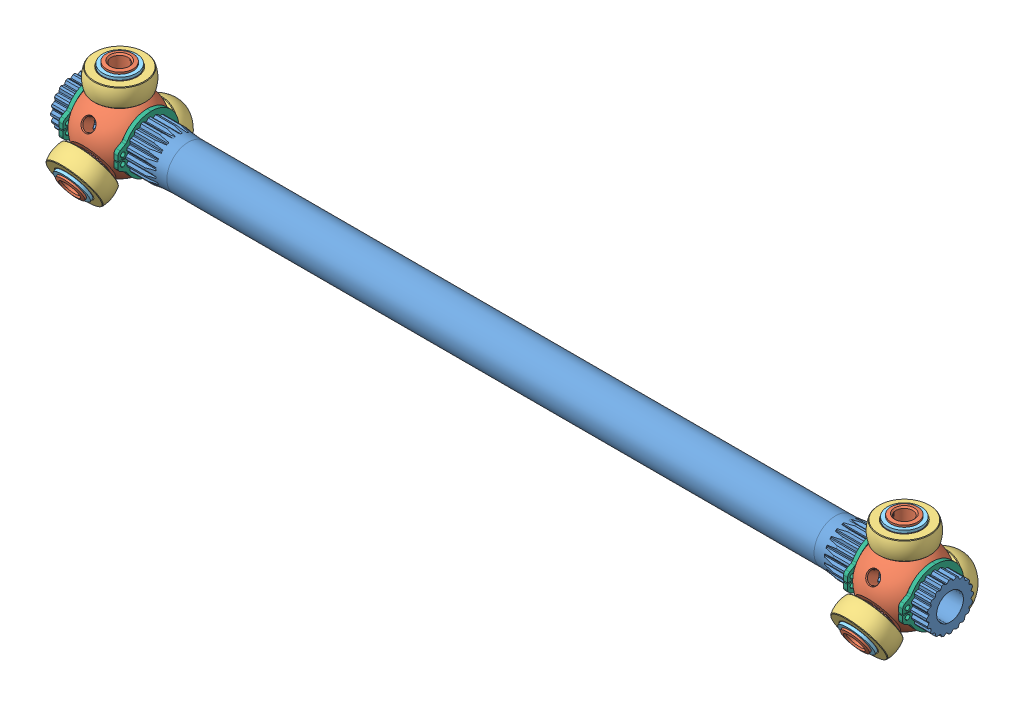
SolidWorks assembly EN-A0104-AB-Half Shaft Assembly, configuration Default. Lengths in mm.
Overall size (412.75 50.64 55.63).
195 component instances, 6 part files, 18 mates.
Components (placement in the parent):
- EN-00030-AB-RCV Half Shaft-1: EN-00030-AB-RCV Half Shaft [Default] at origin size (412.75 22.1 22.1)
- EN-00031-AB-RCV Tripod-1: EN-00031-AB-RCV Tripod [Detailed] at (444.443 -4.946 -19.6967) size (34.45 50.64 55.63)
  - FSAE Tripod V2_1^EN-00031-AB-RCV Tripod-1: FSAE Tripod V2_1^EN-00031-AB-RCV Tripod [Default] at (-43.6945 4.946 19.6967) size (34.45 46.11 52.87) (virtual)
  - FSAE roller_2451_2^EN-00031-AB-RCV Tripod-2: FSAE roller_2451_2^EN-00031-AB-RCV Tripod [Default] at (-43.6945 -7.4365 41.1438) x (0 0.5 -0.866025) z (1 0 0) size (8.74 25.48 25.48) (virtual)
  - FSAE roller_2451_2^EN-00031-AB-RCV Tripod-3: FSAE roller_2451_2^EN-00031-AB-RCV Tripod [Default] at (-43.6945 -7.4365 -1.7504) x (0 0.5 0.866025) z (-1 0 0) size (8.74 25.48 25.48) (virtual)
  - FSAE roller_2451_2^EN-00031-AB-RCV Tripod-4: FSAE roller_2451_2^EN-00031-AB-RCV Tripod [Default] at (-43.6945 29.711 19.6967) x (0 -1 0) z (-1 0 0) size (8.74 25.48 25.48) (virtual)
  - needle^EN-00031-AB-RCV Tripod-1: needle^EN-00031-AB-RCV Tripod [Default] at (-42.3538 -7.5483 -1.6859) x (1 0 0) z (0 0.5 0.866025) size (1.5 1.5 10.16) (virtual)
  - needle^EN-00031-AB-RCV Tripod-2: needle^EN-00031-AB-RCV Tripod [Default] at (-42.3574 -7.2961 -1.8314) x (0.976635 0.186114 -0.107453) z (0 0.5 0.866025) size (1.5 1.5 10.16) (virtual)
  - needle^EN-00031-AB-RCV Tripod-3: needle^EN-00031-AB-RCV Tripod [Default] at (-42.4235 -7.0506 -1.9732) x (0.907631 0.363531 -0.209884) z (0 0.5 0.866025) size (1.5 1.5 10.16) (virtual)
  - needle^EN-00031-AB-RCV Tripod-4: needle^EN-00031-AB-RCV Tripod [Default] at (-42.5489 -6.823 -2.1046) x (0.796213 0.523959 -0.302508) z (0 0.5 0.866025) size (1.5 1.5 10.16) (virtual)
  - needle^EN-00031-AB-RCV Tripod-5: needle^EN-00031-AB-RCV Tripod [Default] at (-42.7279 -6.6242 -2.2194) x (0.647588 0.659903 -0.380995) z (0 0.5 0.866025) size (1.5 1.5 10.16) (virtual)
  - needle^EN-00031-AB-RCV Tripod-6: needle^EN-00031-AB-RCV Tripod [Default] at (-42.9521 -6.4632 -2.3123) x (0.468701 0.76501 -0.441678) z (0 0.5 0.866025) size (1.5 1.5 10.16) (virtual)
  - needle^EN-00031-AB-RCV Tripod-7: needle^EN-00031-AB-RCV Tripod [Default] at (-43.2109 -6.3478 -2.3789) x (0.267911 0.834367 -0.481722) z (0 0.5 0.866025) size (1.5 1.5 10.16) (virtual)
  - needle^EN-00031-AB-RCV Tripod-8: needle^EN-00031-AB-RCV Tripod [Default] at (-43.4924 -6.2833 -2.4162) x (0.054602 0.864733 -0.499254) z (0 0.5 0.866025) size (1.5 1.5 10.16) (virtual)
  - needle^EN-00031-AB-RCV Tripod-9: needle^EN-00031-AB-RCV Tripod [Default] at (-43.7833 -6.2726 -2.4224) x (-0.161259 0.854691 -0.493456) z (0 0.5 0.866025) size (1.5 1.5 10.16) (virtual)
  - needle^EN-00031-AB-RCV Tripod-10: needle^EN-00031-AB-RCV Tripod [Default] at (-44.07 -6.3163 -2.3971) x (-0.369585 0.804708 -0.464599) z (0 0.5 0.866025) size (1.5 1.5 10.16) (virtual)
  - needle^EN-00031-AB-RCV Tripod-11: needle^EN-00031-AB-RCV Tripod [Default] at (-44.3392 -6.4124 -2.3417) x (-0.560639 0.717121 -0.41403) z (0 0.5 0.866025) size (1.5 1.5 10.16) (virtual)
  - needle^EN-00031-AB-RCV Tripod-12: needle^EN-00031-AB-RCV Tripod [Default] at (-44.5783 -6.5563 -2.2586) x (-0.725495 0.596023 -0.344114) z (0 0.5 0.866025) size (1.5 1.5 10.16) (virtual)
  - needle^EN-00031-AB-RCV Tripod-13: needle^EN-00031-AB-RCV Tripod [Default] at (-44.7761 -6.7413 -2.1517) x (-0.856447 0.447072 -0.258117) z (0 0.5 0.866025) size (1.5 1.5 10.16) (virtual)
  - needle^EN-00031-AB-RCV Tripod-14: needle^EN-00031-AB-RCV Tripod [Default] at (-44.9233 -6.9589 -2.0261) x (-0.947378 0.277229 -0.160058) z (0 0.5 0.866025) size (1.5 1.5 10.16) (virtual)
  - needle^EN-00031-AB-RCV Tripod-15: needle^EN-00031-AB-RCV Tripod [Default] at (-45.0131 -7.1987 -1.8877) x (-0.994037 0.094432 -0.05452) z (0 0.5 0.866025) size (1.5 1.5 10.16) (virtual)
  - needle^EN-00031-AB-RCV Tripod-16: needle^EN-00031-AB-RCV Tripod [Default] at (-45.0413 -7.4497 -1.7428) x (-0.994245 -0.092779 0.053566) z (0 0.5 0.866025) size (1.5 1.5 10.16) (virtual)
  - needle^EN-00031-AB-RCV Tripod-17: needle^EN-00031-AB-RCV Tripod [Default] at (-45.0065 -7.7 -1.5982) x (-0.947991 -0.275654 0.159149) z (0 0.5 0.866025) size (1.5 1.5 10.16) (virtual)
  - needle^EN-00031-AB-RCV Tripod-18: needle^EN-00031-AB-RCV Tripod [Default] at (-44.9105 -7.9381 -1.4608) x (-0.857437 -0.445647 0.257295) z (0 0.5 0.866025) size (1.5 1.5 10.16) (virtual)
  - needle^EN-00031-AB-RCV Tripod-19: needle^EN-00031-AB-RCV Tripod [Default] at (-44.7576 -8.1527 -1.3369) x (-0.726814 -0.594816 0.343417) z (0 0.5 0.866025) size (1.5 1.5 10.16) (virtual)
  - needle^EN-00031-AB-RCV Tripod-20: needle^EN-00031-AB-RCV Tripod [Default] at (-44.555 -8.3338 -1.2323) x (-0.562228 -0.716188 0.413491) z (0 0.5 0.866025) size (1.5 1.5 10.16) (virtual)
  - needle^EN-00031-AB-RCV Tripod-21: needle^EN-00031-AB-RCV Tripod [Default] at (-44.3122 -8.473 -1.152) x (-0.371368 -0.804092 0.464243) z (0 0.5 0.866025) size (1.5 1.5 10.16) (virtual)
  - needle^EN-00031-AB-RCV Tripod-22: needle^EN-00031-AB-RCV Tripod [Default] at (-44.0406 -8.5637 -1.0996) x (-0.163154 -0.854421 0.4933) z (0 0.5 0.866025) size (1.5 1.5 10.16) (virtual)
  - needle^EN-00031-AB-RCV Tripod-23: needle^EN-00031-AB-RCV Tripod [Default] at (-43.7528 -8.6018 -1.0776) x (0.052685 -0.864823 0.499306) z (0 0.5 0.866025) size (1.5 1.5 10.16) (virtual)
  - needle^EN-00031-AB-RCV Tripod-24: needle^EN-00031-AB-RCV Tripod [Default] at (-43.4622 -8.5854 -1.0871) x (0.266061 -0.834811 0.481978) z (0 0.5 0.866025) size (1.5 1.5 10.16) (virtual)
  - needle^EN-00031-AB-RCV Tripod-25: needle^EN-00031-AB-RCV Tripod [Default] at (-43.1825 -8.5153 -1.1275) x (0.467004 -0.765787 0.442128) z (0 0.5 0.866025) size (1.5 1.5 10.16) (virtual)
  - needle^EN-00031-AB-RCV Tripod-26: needle^EN-00031-AB-RCV Tripod [Default] at (-42.9268 -8.3949 -1.1971) x (0.646124 -0.660979 0.381616) z (0 0.5 0.866025) size (1.5 1.5 10.16) (virtual)
  - needle^EN-00031-AB-RCV Tripod-27: needle^EN-00031-AB-RCV Tripod [Default] at (-42.7069 -8.2296 -1.2925) x (0.79505 -0.525282 0.303272) z (0 0.5 0.866025) size (1.5 1.5 10.16) (virtual)
  - needle^EN-00031-AB-RCV Tripod-28: needle^EN-00031-AB-RCV Tripod [Default] at (-42.5332 -8.0272 -1.4093) x (0.906823 -0.365039 0.210755) z (0 0.5 0.866025) size (1.5 1.5 10.16) (virtual)
  - needle^EN-00031-AB-RCV Tripod-29: needle^EN-00031-AB-RCV Tripod [Default] at (-42.4137 -7.7973 -1.5421) x (0.97622 -0.187737 0.10839) z (0 0.5 0.866025) size (1.5 1.5 10.16) (virtual)
  - needle^EN-00031-AB-RCV Tripod-30: needle^EN-00031-AB-RCV Tripod [Default] at (-42.3538 29.711 19.5676) x (1 0 0) z (0 -1 0) size (1.5 1.5 10.16) (virtual)
  - needle^EN-00031-AB-RCV Tripod-31: needle^EN-00031-AB-RCV Tripod [Default] at (-42.3538 -7.3247 41.2084) x (1 0 0) z (0 0.5 -0.866025) size (1.5 1.5 10.16) (virtual)
  - needle^EN-00031-AB-RCV Tripod-32: needle^EN-00031-AB-RCV Tripod [Default] at (-42.4137 29.711 19.2801) x (0.97622 0 -0.21678) z (0 -1 0) size (1.5 1.5 10.16) (virtual)
  - needle^EN-00031-AB-RCV Tripod-33: needle^EN-00031-AB-RCV Tripod [Default] at (-42.4137 -7.0756 41.3522) x (0.97622 0.187737 0.10839) z (0 0.5 -0.866025) size (1.5 1.5 10.16) (virtual)
  - needle^EN-00031-AB-RCV Tripod-34: needle^EN-00031-AB-RCV Tripod [Default] at (-42.5332 29.711 19.0146) x (0.906823 0 -0.421511) z (0 -1 0) size (1.5 1.5 10.16) (virtual)
  - needle^EN-00031-AB-RCV Tripod-35: needle^EN-00031-AB-RCV Tripod [Default] at (-42.5332 -6.8457 41.4849) x (0.906823 0.365039 0.210755) z (0 0.5 -0.866025) size (1.5 1.5 10.16) (virtual)
  - needle^EN-00031-AB-RCV Tripod-36: needle^EN-00031-AB-RCV Tripod [Default] at (-42.7069 29.711 18.7809) x (0.79505 0 -0.606544) z (0 -1 0) size (1.5 1.5 10.16) (virtual)
  - needle^EN-00031-AB-RCV Tripod-37: needle^EN-00031-AB-RCV Tripod [Default] at (-42.7069 -6.6434 41.6017) x (0.79505 0.525282 0.303272) z (0 0.5 -0.866025) size (1.5 1.5 10.16) (virtual)
  - needle^EN-00031-AB-RCV Tripod-38: needle^EN-00031-AB-RCV Tripod [Default] at (-42.9268 29.711 18.5901) x (0.646124 0 -0.763232) z (0 -1 0) size (1.5 1.5 10.16) (virtual)
  - needle^EN-00031-AB-RCV Tripod-39: needle^EN-00031-AB-RCV Tripod [Default] at (-42.9268 -6.4781 41.6972) x (0.646124 0.660979 0.381616) z (0 0.5 -0.866025) size (1.5 1.5 10.16) (virtual)
  - needle^EN-00031-AB-RCV Tripod-40: needle^EN-00031-AB-RCV Tripod [Default] at (-43.1825 29.711 18.4509) x (0.467004 0 -0.884255) z (0 -1 0) size (1.5 1.5 10.16) (virtual)
  - needle^EN-00031-AB-RCV Tripod-41: needle^EN-00031-AB-RCV Tripod [Default] at (-43.1825 -6.3576 41.7667) x (0.467004 0.765787 0.442128) z (0 0.5 -0.866025) size (1.5 1.5 10.16) (virtual)
  - needle^EN-00031-AB-RCV Tripod-42: needle^EN-00031-AB-RCV Tripod [Default] at (-43.4622 29.711 18.37) x (0.266061 0 -0.963956) z (0 -1 0) size (1.5 1.5 10.16) (virtual)
  - needle^EN-00031-AB-RCV Tripod-43: needle^EN-00031-AB-RCV Tripod [Default] at (-43.4622 -6.2875 41.8072) x (0.266061 0.834811 0.481978) z (0 0.5 -0.866025) size (1.5 1.5 10.16) (virtual)
  - needle^EN-00031-AB-RCV Tripod-44: needle^EN-00031-AB-RCV Tripod [Default] at (-43.7528 29.711 18.3511) x (0.052685 0 -0.998611) z (0 -1 0) size (1.5 1.5 10.16) (virtual)
  - needle^EN-00031-AB-RCV Tripod-45: needle^EN-00031-AB-RCV Tripod [Default] at (-43.7528 -6.2711 41.8166) x (0.052685 0.864823 0.499306) z (0 0.5 -0.866025) size (1.5 1.5 10.16) (virtual)
  - needle^EN-00031-AB-RCV Tripod-46: needle^EN-00031-AB-RCV Tripod [Default] at (-44.0406 29.711 18.3951) x (-0.163154 0 -0.986601) z (0 -1 0) size (1.5 1.5 10.16) (virtual)
  - needle^EN-00031-AB-RCV Tripod-47: needle^EN-00031-AB-RCV Tripod [Default] at (-44.0406 -6.3092 41.7947) x (-0.163154 0.854421 0.4933) z (0 0.5 -0.866025) size (1.5 1.5 10.16) (virtual)
  - needle^EN-00031-AB-RCV Tripod-48: needle^EN-00031-AB-RCV Tripod [Default] at (-44.3122 29.711 18.4999) x (-0.371368 0 -0.928486) z (0 -1 0) size (1.5 1.5 10.16) (virtual)
  - needle^EN-00031-AB-RCV Tripod-49: needle^EN-00031-AB-RCV Tripod [Default] at (-44.3122 -6.4 41.7423) x (-0.371368 0.804092 0.464243) z (0 0.5 -0.866025) size (1.5 1.5 10.16) (virtual)
  - needle^EN-00031-AB-RCV Tripod-50: needle^EN-00031-AB-RCV Tripod [Default] at (-44.555 29.711 18.6606) x (-0.562228 0 -0.826982) z (0 -1 0) size (1.5 1.5 10.16) (virtual)
  - needle^EN-00031-AB-RCV Tripod-51: needle^EN-00031-AB-RCV Tripod [Default] at (-44.555 -6.5392 41.6619) x (-0.562228 0.716188 0.413491) z (0 0.5 -0.866025) size (1.5 1.5 10.16) (virtual)
  - needle^EN-00031-AB-RCV Tripod-52: needle^EN-00031-AB-RCV Tripod [Default] at (-44.7576 29.711 18.8697) x (-0.726814 0 -0.686834) z (0 -1 0) size (1.5 1.5 10.16) (virtual)
  - needle^EN-00031-AB-RCV Tripod-53: needle^EN-00031-AB-RCV Tripod [Default] at (-44.7576 -6.7203 41.5573) x (-0.726814 0.594816 0.343417) z (0 0.5 -0.866025) size (1.5 1.5 10.16) (virtual)
  - needle^EN-00031-AB-RCV Tripod-54: needle^EN-00031-AB-RCV Tripod [Default] at (-44.9105 29.711 19.1175) x (-0.857437 0 -0.514589) z (0 -1 0) size (1.5 1.5 10.16) (virtual)
  - needle^EN-00031-AB-RCV Tripod-55: needle^EN-00031-AB-RCV Tripod [Default] at (-44.9105 -6.9349 41.4334) x (-0.857437 0.445647 0.257295) z (0 0.5 -0.866025) size (1.5 1.5 10.16) (virtual)
  - needle^EN-00031-AB-RCV Tripod-56: needle^EN-00031-AB-RCV Tripod [Default] at (-45.0065 29.711 19.3924) x (-0.947991 0 -0.318298) z (0 -1 0) size (1.5 1.5 10.16) (virtual)
  - needle^EN-00031-AB-RCV Tripod-57: needle^EN-00031-AB-RCV Tripod [Default] at (-45.0065 -7.1729 41.296) x (-0.947991 0.275654 0.159149) z (0 0.5 -0.866025) size (1.5 1.5 10.16) (virtual)
  - needle^EN-00031-AB-RCV Tripod-58: needle^EN-00031-AB-RCV Tripod [Default] at (-45.0413 29.711 19.6814) x (-0.994245 0 -0.107132) z (0 -1 0) size (1.5 1.5 10.16) (virtual)
  - needle^EN-00031-AB-RCV Tripod-59: needle^EN-00031-AB-RCV Tripod [Default] at (-45.0413 -7.4232 41.1515) x (-0.994245 0.092779 0.053566) z (0 0.5 -0.866025) size (1.5 1.5 10.16) (virtual)
  - needle^EN-00031-AB-RCV Tripod-60: needle^EN-00031-AB-RCV Tripod [Default] at (-45.0131 29.711 19.9712) x (-0.994037 0 0.10904) z (0 -1 0) size (1.5 1.5 10.16) (virtual)
  - needle^EN-00031-AB-RCV Tripod-61: needle^EN-00031-AB-RCV Tripod [Default] at (-45.0131 -7.6742 41.0066) x (-0.994037 -0.094432 -0.05452) z (0 0.5 -0.866025) size (1.5 1.5 10.16) (virtual)
  - needle^EN-00031-AB-RCV Tripod-62: needle^EN-00031-AB-RCV Tripod [Default] at (-44.9233 29.711 20.2482) x (-0.947378 0 0.320117) z (0 -1 0) size (1.5 1.5 10.16) (virtual)
  - needle^EN-00031-AB-RCV Tripod-63: needle^EN-00031-AB-RCV Tripod [Default] at (-44.9233 -7.914 40.8681) x (-0.947378 -0.277229 -0.160058) z (0 0.5 -0.866025) size (1.5 1.5 10.16) (virtual)
  - needle^EN-00031-AB-RCV Tripod-64: needle^EN-00031-AB-RCV Tripod [Default] at (-44.7761 29.711 20.4994) x (-0.856447 0 0.516234) z (0 -1 0) size (1.5 1.5 10.16) (virtual)
  - needle^EN-00031-AB-RCV Tripod-65: needle^EN-00031-AB-RCV Tripod [Default] at (-44.7761 -8.1316 40.7425) x (-0.856447 -0.447072 -0.258117) z (0 0.5 -0.866025) size (1.5 1.5 10.16) (virtual)
  - needle^EN-00031-AB-RCV Tripod-66: needle^EN-00031-AB-RCV Tripod [Default] at (-44.5783 29.711 20.7131) x (-0.725495 0 0.688228) z (0 -1 0) size (1.5 1.5 10.16) (virtual)
  - needle^EN-00031-AB-RCV Tripod-67: needle^EN-00031-AB-RCV Tripod [Default] at (-44.5783 -8.3166 40.6357) x (-0.725495 -0.596023 -0.344114) z (0 0.5 -0.866025) size (1.5 1.5 10.16) (virtual)
  - needle^EN-00031-AB-RCV Tripod-68: needle^EN-00031-AB-RCV Tripod [Default] at (-44.3392 29.711 20.8792) x (-0.560639 0 0.82806) z (0 -1 0) size (1.5 1.5 10.16) (virtual)
  - needle^EN-00031-AB-RCV Tripod-69: needle^EN-00031-AB-RCV Tripod [Default] at (-44.3392 -8.4606 40.5526) x (-0.560639 -0.717121 -0.41403) z (0 0.5 -0.866025) size (1.5 1.5 10.16) (virtual)
  - needle^EN-00031-AB-RCV Tripod-70: needle^EN-00031-AB-RCV Tripod [Default] at (-44.07 29.711 20.9902) x (-0.369585 0 0.929197) z (0 -1 0) size (1.5 1.5 10.16) (virtual)
  - needle^EN-00031-AB-RCV Tripod-71: needle^EN-00031-AB-RCV Tripod [Default] at (-44.07 -8.5566 40.4971) x (-0.369585 -0.804708 -0.464599) z (0 0.5 -0.866025) size (1.5 1.5 10.16) (virtual)
  - needle^EN-00031-AB-RCV Tripod-72: needle^EN-00031-AB-RCV Tripod [Default] at (-43.7833 29.711 21.0407) x (-0.161259 0 0.986912) z (0 -1 0) size (1.5 1.5 10.16) (virtual)
  - needle^EN-00031-AB-RCV Tripod-73: needle^EN-00031-AB-RCV Tripod [Default] at (-43.7833 -8.6003 40.4719) x (-0.161259 -0.854691 -0.493456) z (0 0.5 -0.866025) size (1.5 1.5 10.16) (virtual)
  - needle^EN-00031-AB-RCV Tripod-74: needle^EN-00031-AB-RCV Tripod [Default] at (-43.4924 29.711 21.0283) x (0.054602 0 0.998508) z (0 -1 0) size (1.5 1.5 10.16) (virtual)
  - needle^EN-00031-AB-RCV Tripod-75: needle^EN-00031-AB-RCV Tripod [Default] at (-43.4924 -8.5897 40.478) x (0.054602 -0.864733 -0.499254) z (0 0.5 -0.866025) size (1.5 1.5 10.16) (virtual)
  - needle^EN-00031-AB-RCV Tripod-76: needle^EN-00031-AB-RCV Tripod [Default] at (-43.2109 29.711 20.9538) x (0.267911 0 0.963444) z (0 -1 0) size (1.5 1.5 10.16) (virtual)
  - needle^EN-00031-AB-RCV Tripod-77: needle^EN-00031-AB-RCV Tripod [Default] at (-43.2109 -8.5251 40.5153) x (0.267911 -0.834367 -0.481722) z (0 0.5 -0.866025) size (1.5 1.5 10.16) (virtual)
  - needle^EN-00031-AB-RCV Tripod-78: needle^EN-00031-AB-RCV Tripod [Default] at (-42.9521 29.711 20.8205) x (0.468701 0 0.883357) z (0 -1 0) size (1.5 1.5 10.16) (virtual)
  - needle^EN-00031-AB-RCV Tripod-79: needle^EN-00031-AB-RCV Tripod [Default] at (-42.9521 -8.4097 40.582) x (0.468701 -0.76501 -0.441678) z (0 0.5 -0.866025) size (1.5 1.5 10.16) (virtual)
  - needle^EN-00031-AB-RCV Tripod-80: needle^EN-00031-AB-RCV Tripod [Default] at (-42.7279 29.711 20.6347) x (0.647588 0 0.761991) z (0 -1 0) size (1.5 1.5 10.16) (virtual)
  - needle^EN-00031-AB-RCV Tripod-81: needle^EN-00031-AB-RCV Tripod [Default] at (-42.7279 -8.2488 40.6749) x (0.647588 -0.659903 -0.380995) z (0 0.5 -0.866025) size (1.5 1.5 10.16) (virtual)
  - needle^EN-00031-AB-RCV Tripod-82: needle^EN-00031-AB-RCV Tripod [Default] at (-42.5489 29.711 20.4051) x (0.796213 0 0.605016) z (0 -1 0) size (1.5 1.5 10.16) (virtual)
  - needle^EN-00031-AB-RCV Tripod-83: needle^EN-00031-AB-RCV Tripod [Default] at (-42.5489 -8.0499 40.7897) x (0.796213 -0.523959 -0.302508) z (0 0.5 -0.866025) size (1.5 1.5 10.16) (virtual)
  - needle^EN-00031-AB-RCV Tripod-84: needle^EN-00031-AB-RCV Tripod [Default] at (-42.4235 29.711 20.1423) x (0.907631 0 0.419769) z (0 -1 0) size (1.5 1.5 10.16) (virtual)
  - needle^EN-00031-AB-RCV Tripod-85: needle^EN-00031-AB-RCV Tripod [Default] at (-42.4235 -7.8224 40.921) x (0.907631 -0.363531 -0.209884) z (0 0.5 -0.866025) size (1.5 1.5 10.16) (virtual)
  - needle^EN-00031-AB-RCV Tripod-86: needle^EN-00031-AB-RCV Tripod [Default] at (-42.3574 29.711 19.8588) x (0.976635 0 0.214906) z (0 -1 0) size (1.5 1.5 10.16) (virtual)
  - needle^EN-00031-AB-RCV Tripod-87: needle^EN-00031-AB-RCV Tripod [Default] at (-42.3574 -7.5768 41.0628) x (0.976635 -0.186114 -0.107453) z (0 0.5 -0.866025) size (1.5 1.5 10.16) (virtual)
  - Tripod Retainer^EN-00031-AB-RCV Tripod-1: Tripod Retainer^EN-00031-AB-RCV Tripod [Default] at (-43.6945 -8.0715 -2.8502) x (0.973299 0.198788 -0.11477) z (0 0.5 0.866025) size (15.88 15.88 1.27) (virtual)
  - Tripod Retainer^EN-00031-AB-RCV Tripod-2: Tripod Retainer^EN-00031-AB-RCV Tripod [Default] at (-43.6945 -8.0715 42.2437) x (0.973299 -0.198788 -0.11477) z (0 0.5 -0.866025) size (15.88 15.88 1.27) (virtual)
  - Tripod Retainer^EN-00031-AB-RCV Tripod-3: Tripod Retainer^EN-00031-AB-RCV Tripod [Default] at (-43.6945 30.981 19.6967) x (0.973299 0 0.229541) z (0 -1 0) size (15.88 15.88 1.27) (virtual)
- EN-00031-AB-RCV Tripod-2: EN-00031-AB-RCV Tripod [Detailed] at (74.746 -4.946 -19.6967) size (34.45 50.64 55.63)
  - FSAE Tripod V2_1^EN-00031-AB-RCV Tripod-1: FSAE Tripod V2_1^EN-00031-AB-RCV Tripod [Default] at (-43.6945 4.946 19.6967) size (34.45 46.11 52.87) (virtual)
  - FSAE roller_2451_2^EN-00031-AB-RCV Tripod-2: FSAE roller_2451_2^EN-00031-AB-RCV Tripod [Default] at (-43.6945 -7.4365 41.1438) x (0 0.5 -0.866025) z (1 0 0) size (8.74 25.48 25.48) (virtual)
  - FSAE roller_2451_2^EN-00031-AB-RCV Tripod-3: FSAE roller_2451_2^EN-00031-AB-RCV Tripod [Default] at (-43.6945 -7.4365 -1.7504) x (0 0.5 0.866025) z (-1 0 0) size (8.74 25.48 25.48) (virtual)
  - FSAE roller_2451_2^EN-00031-AB-RCV Tripod-4: FSAE roller_2451_2^EN-00031-AB-RCV Tripod [Default] at (-43.6945 29.711 19.6967) x (0 -1 0) z (-1 0 0) size (8.74 25.48 25.48) (virtual)
  - needle^EN-00031-AB-RCV Tripod-1: needle^EN-00031-AB-RCV Tripod [Default] at (-42.3538 -7.5483 -1.6859) x (1 0 0) z (0 0.5 0.866025) size (1.5 1.5 10.16) (virtual)
  - needle^EN-00031-AB-RCV Tripod-2: needle^EN-00031-AB-RCV Tripod [Default] at (-42.3574 -7.2961 -1.8314) x (0.976635 0.186114 -0.107453) z (0 0.5 0.866025) size (1.5 1.5 10.16) (virtual)
  - needle^EN-00031-AB-RCV Tripod-3: needle^EN-00031-AB-RCV Tripod [Default] at (-42.4235 -7.0506 -1.9732) x (0.907631 0.363531 -0.209884) z (0 0.5 0.866025) size (1.5 1.5 10.16) (virtual)
  - needle^EN-00031-AB-RCV Tripod-4: needle^EN-00031-AB-RCV Tripod [Default] at (-42.5489 -6.823 -2.1046) x (0.796213 0.523959 -0.302508) z (0 0.5 0.866025) size (1.5 1.5 10.16) (virtual)
  - needle^EN-00031-AB-RCV Tripod-5: needle^EN-00031-AB-RCV Tripod [Default] at (-42.7279 -6.6242 -2.2194) x (0.647588 0.659903 -0.380995) z (0 0.5 0.866025) size (1.5 1.5 10.16) (virtual)
  - needle^EN-00031-AB-RCV Tripod-6: needle^EN-00031-AB-RCV Tripod [Default] at (-42.9521 -6.4632 -2.3123) x (0.468701 0.76501 -0.441678) z (0 0.5 0.866025) size (1.5 1.5 10.16) (virtual)
  - needle^EN-00031-AB-RCV Tripod-7: needle^EN-00031-AB-RCV Tripod [Default] at (-43.2109 -6.3478 -2.3789) x (0.267911 0.834367 -0.481722) z (0 0.5 0.866025) size (1.5 1.5 10.16) (virtual)
  - needle^EN-00031-AB-RCV Tripod-8: needle^EN-00031-AB-RCV Tripod [Default] at (-43.4924 -6.2833 -2.4162) x (0.054602 0.864733 -0.499254) z (0 0.5 0.866025) size (1.5 1.5 10.16) (virtual)
  - needle^EN-00031-AB-RCV Tripod-9: needle^EN-00031-AB-RCV Tripod [Default] at (-43.7833 -6.2726 -2.4224) x (-0.161259 0.854691 -0.493456) z (0 0.5 0.866025) size (1.5 1.5 10.16) (virtual)
  - needle^EN-00031-AB-RCV Tripod-10: needle^EN-00031-AB-RCV Tripod [Default] at (-44.07 -6.3163 -2.3971) x (-0.369585 0.804708 -0.464599) z (0 0.5 0.866025) size (1.5 1.5 10.16) (virtual)
  - needle^EN-00031-AB-RCV Tripod-11: needle^EN-00031-AB-RCV Tripod [Default] at (-44.3392 -6.4124 -2.3417) x (-0.560639 0.717121 -0.41403) z (0 0.5 0.866025) size (1.5 1.5 10.16) (virtual)
  - needle^EN-00031-AB-RCV Tripod-12: needle^EN-00031-AB-RCV Tripod [Default] at (-44.5783 -6.5563 -2.2586) x (-0.725495 0.596023 -0.344114) z (0 0.5 0.866025) size (1.5 1.5 10.16) (virtual)
  - needle^EN-00031-AB-RCV Tripod-13: needle^EN-00031-AB-RCV Tripod [Default] at (-44.7761 -6.7413 -2.1517) x (-0.856447 0.447072 -0.258117) z (0 0.5 0.866025) size (1.5 1.5 10.16) (virtual)
  - needle^EN-00031-AB-RCV Tripod-14: needle^EN-00031-AB-RCV Tripod [Default] at (-44.9233 -6.9589 -2.0261) x (-0.947378 0.277229 -0.160058) z (0 0.5 0.866025) size (1.5 1.5 10.16) (virtual)
  - needle^EN-00031-AB-RCV Tripod-15: needle^EN-00031-AB-RCV Tripod [Default] at (-45.0131 -7.1987 -1.8877) x (-0.994037 0.094432 -0.05452) z (0 0.5 0.866025) size (1.5 1.5 10.16) (virtual)
  - needle^EN-00031-AB-RCV Tripod-16: needle^EN-00031-AB-RCV Tripod [Default] at (-45.0413 -7.4497 -1.7428) x (-0.994245 -0.092779 0.053566) z (0 0.5 0.866025) size (1.5 1.5 10.16) (virtual)
  - needle^EN-00031-AB-RCV Tripod-17: needle^EN-00031-AB-RCV Tripod [Default] at (-45.0065 -7.7 -1.5982) x (-0.947991 -0.275654 0.159149) z (0 0.5 0.866025) size (1.5 1.5 10.16) (virtual)
  - needle^EN-00031-AB-RCV Tripod-18: needle^EN-00031-AB-RCV Tripod [Default] at (-44.9105 -7.9381 -1.4608) x (-0.857437 -0.445647 0.257295) z (0 0.5 0.866025) size (1.5 1.5 10.16) (virtual)
  - needle^EN-00031-AB-RCV Tripod-19: needle^EN-00031-AB-RCV Tripod [Default] at (-44.7576 -8.1527 -1.3369) x (-0.726814 -0.594816 0.343417) z (0 0.5 0.866025) size (1.5 1.5 10.16) (virtual)
  - needle^EN-00031-AB-RCV Tripod-20: needle^EN-00031-AB-RCV Tripod [Default] at (-44.555 -8.3338 -1.2323) x (-0.562228 -0.716188 0.413491) z (0 0.5 0.866025) size (1.5 1.5 10.16) (virtual)
  - needle^EN-00031-AB-RCV Tripod-21: needle^EN-00031-AB-RCV Tripod [Default] at (-44.3122 -8.473 -1.152) x (-0.371368 -0.804092 0.464243) z (0 0.5 0.866025) size (1.5 1.5 10.16) (virtual)
  - needle^EN-00031-AB-RCV Tripod-22: needle^EN-00031-AB-RCV Tripod [Default] at (-44.0406 -8.5637 -1.0996) x (-0.163154 -0.854421 0.4933) z (0 0.5 0.866025) size (1.5 1.5 10.16) (virtual)
  - needle^EN-00031-AB-RCV Tripod-23: needle^EN-00031-AB-RCV Tripod [Default] at (-43.7528 -8.6018 -1.0776) x (0.052685 -0.864823 0.499306) z (0 0.5 0.866025) size (1.5 1.5 10.16) (virtual)
  - needle^EN-00031-AB-RCV Tripod-24: needle^EN-00031-AB-RCV Tripod [Default] at (-43.4622 -8.5854 -1.0871) x (0.266061 -0.834811 0.481978) z (0 0.5 0.866025) size (1.5 1.5 10.16) (virtual)
  - needle^EN-00031-AB-RCV Tripod-25: needle^EN-00031-AB-RCV Tripod [Default] at (-43.1825 -8.5153 -1.1275) x (0.467004 -0.765787 0.442128) z (0 0.5 0.866025) size (1.5 1.5 10.16) (virtual)
  - needle^EN-00031-AB-RCV Tripod-26: needle^EN-00031-AB-RCV Tripod [Default] at (-42.9268 -8.3949 -1.1971) x (0.646124 -0.660979 0.381616) z (0 0.5 0.866025) size (1.5 1.5 10.16) (virtual)
  - needle^EN-00031-AB-RCV Tripod-27: needle^EN-00031-AB-RCV Tripod [Default] at (-42.7069 -8.2296 -1.2925) x (0.79505 -0.525282 0.303272) z (0 0.5 0.866025) size (1.5 1.5 10.16) (virtual)
  - needle^EN-00031-AB-RCV Tripod-28: needle^EN-00031-AB-RCV Tripod [Default] at (-42.5332 -8.0272 -1.4093) x (0.906823 -0.365039 0.210755) z (0 0.5 0.866025) size (1.5 1.5 10.16) (virtual)
  - needle^EN-00031-AB-RCV Tripod-29: needle^EN-00031-AB-RCV Tripod [Default] at (-42.4137 -7.7973 -1.5421) x (0.97622 -0.187737 0.10839) z (0 0.5 0.866025) size (1.5 1.5 10.16) (virtual)
  - needle^EN-00031-AB-RCV Tripod-30: needle^EN-00031-AB-RCV Tripod [Default] at (-42.3538 29.711 19.5676) x (1 0 0) z (0 -1 0) size (1.5 1.5 10.16) (virtual)
  - needle^EN-00031-AB-RCV Tripod-31: needle^EN-00031-AB-RCV Tripod [Default] at (-42.3538 -7.3247 41.2084) x (1 0 0) z (0 0.5 -0.866025) size (1.5 1.5 10.16) (virtual)
  - needle^EN-00031-AB-RCV Tripod-32: needle^EN-00031-AB-RCV Tripod [Default] at (-42.4137 29.711 19.2801) x (0.97622 0 -0.21678) z (0 -1 0) size (1.5 1.5 10.16) (virtual)
  - needle^EN-00031-AB-RCV Tripod-33: needle^EN-00031-AB-RCV Tripod [Default] at (-42.4137 -7.0756 41.3522) x (0.97622 0.187737 0.10839) z (0 0.5 -0.866025) size (1.5 1.5 10.16) (virtual)
  - needle^EN-00031-AB-RCV Tripod-34: needle^EN-00031-AB-RCV Tripod [Default] at (-42.5332 29.711 19.0146) x (0.906823 0 -0.421511) z (0 -1 0) size (1.5 1.5 10.16) (virtual)
  - needle^EN-00031-AB-RCV Tripod-35: needle^EN-00031-AB-RCV Tripod [Default] at (-42.5332 -6.8457 41.4849) x (0.906823 0.365039 0.210755) z (0 0.5 -0.866025) size (1.5 1.5 10.16) (virtual)
  - needle^EN-00031-AB-RCV Tripod-36: needle^EN-00031-AB-RCV Tripod [Default] at (-42.7069 29.711 18.7809) x (0.79505 0 -0.606544) z (0 -1 0) size (1.5 1.5 10.16) (virtual)
  - needle^EN-00031-AB-RCV Tripod-37: needle^EN-00031-AB-RCV Tripod [Default] at (-42.7069 -6.6434 41.6017) x (0.79505 0.525282 0.303272) z (0 0.5 -0.866025) size (1.5 1.5 10.16) (virtual)
  - needle^EN-00031-AB-RCV Tripod-38: needle^EN-00031-AB-RCV Tripod [Default] at (-42.9268 29.711 18.5901) x (0.646124 0 -0.763232) z (0 -1 0) size (1.5 1.5 10.16) (virtual)
  - needle^EN-00031-AB-RCV Tripod-39: needle^EN-00031-AB-RCV Tripod [Default] at (-42.9268 -6.4781 41.6972) x (0.646124 0.660979 0.381616) z (0 0.5 -0.866025) size (1.5 1.5 10.16) (virtual)
  - needle^EN-00031-AB-RCV Tripod-40: needle^EN-00031-AB-RCV Tripod [Default] at (-43.1825 29.711 18.4509) x (0.467004 0 -0.884255) z (0 -1 0) size (1.5 1.5 10.16) (virtual)
  - needle^EN-00031-AB-RCV Tripod-41: needle^EN-00031-AB-RCV Tripod [Default] at (-43.1825 -6.3576 41.7667) x (0.467004 0.765787 0.442128) z (0 0.5 -0.866025) size (1.5 1.5 10.16) (virtual)
  - needle^EN-00031-AB-RCV Tripod-42: needle^EN-00031-AB-RCV Tripod [Default] at (-43.4622 29.711 18.37) x (0.266061 0 -0.963956) z (0 -1 0) size (1.5 1.5 10.16) (virtual)
  - needle^EN-00031-AB-RCV Tripod-43: needle^EN-00031-AB-RCV Tripod [Default] at (-43.4622 -6.2875 41.8072) x (0.266061 0.834811 0.481978) z (0 0.5 -0.866025) size (1.5 1.5 10.16) (virtual)
  - needle^EN-00031-AB-RCV Tripod-44: needle^EN-00031-AB-RCV Tripod [Default] at (-43.7528 29.711 18.3511) x (0.052685 0 -0.998611) z (0 -1 0) size (1.5 1.5 10.16) (virtual)
  - needle^EN-00031-AB-RCV Tripod-45: needle^EN-00031-AB-RCV Tripod [Default] at (-43.7528 -6.2711 41.8166) x (0.052685 0.864823 0.499306) z (0 0.5 -0.866025) size (1.5 1.5 10.16) (virtual)
  - needle^EN-00031-AB-RCV Tripod-46: needle^EN-00031-AB-RCV Tripod [Default] at (-44.0406 29.711 18.3951) x (-0.163154 0 -0.986601) z (0 -1 0) size (1.5 1.5 10.16) (virtual)
  - needle^EN-00031-AB-RCV Tripod-47: needle^EN-00031-AB-RCV Tripod [Default] at (-44.0406 -6.3092 41.7947) x (-0.163154 0.854421 0.4933) z (0 0.5 -0.866025) size (1.5 1.5 10.16) (virtual)
  - needle^EN-00031-AB-RCV Tripod-48: needle^EN-00031-AB-RCV Tripod [Default] at (-44.3122 29.711 18.4999) x (-0.371368 0 -0.928486) z (0 -1 0) size (1.5 1.5 10.16) (virtual)
  - needle^EN-00031-AB-RCV Tripod-49: needle^EN-00031-AB-RCV Tripod [Default] at (-44.3122 -6.4 41.7423) x (-0.371368 0.804092 0.464243) z (0 0.5 -0.866025) size (1.5 1.5 10.16) (virtual)
  - needle^EN-00031-AB-RCV Tripod-50: needle^EN-00031-AB-RCV Tripod [Default] at (-44.555 29.711 18.6606) x (-0.562228 0 -0.826982) z (0 -1 0) size (1.5 1.5 10.16) (virtual)
  - needle^EN-00031-AB-RCV Tripod-51: needle^EN-00031-AB-RCV Tripod [Default] at (-44.555 -6.5392 41.6619) x (-0.562228 0.716188 0.413491) z (0 0.5 -0.866025) size (1.5 1.5 10.16) (virtual)
  - needle^EN-00031-AB-RCV Tripod-52: needle^EN-00031-AB-RCV Tripod [Default] at (-44.7576 29.711 18.8697) x (-0.726814 0 -0.686834) z (0 -1 0) size (1.5 1.5 10.16) (virtual)
  - needle^EN-00031-AB-RCV Tripod-53: needle^EN-00031-AB-RCV Tripod [Default] at (-44.7576 -6.7203 41.5573) x (-0.726814 0.594816 0.343417) z (0 0.5 -0.866025) size (1.5 1.5 10.16) (virtual)
  - needle^EN-00031-AB-RCV Tripod-54: needle^EN-00031-AB-RCV Tripod [Default] at (-44.9105 29.711 19.1175) x (-0.857437 0 -0.514589) z (0 -1 0) size (1.5 1.5 10.16) (virtual)
  - needle^EN-00031-AB-RCV Tripod-55: needle^EN-00031-AB-RCV Tripod [Default] at (-44.9105 -6.9349 41.4334) x (-0.857437 0.445647 0.257295) z (0 0.5 -0.866025) size (1.5 1.5 10.16) (virtual)
  - needle^EN-00031-AB-RCV Tripod-56: needle^EN-00031-AB-RCV Tripod [Default] at (-45.0065 29.711 19.3924) x (-0.947991 0 -0.318298) z (0 -1 0) size (1.5 1.5 10.16) (virtual)
  - needle^EN-00031-AB-RCV Tripod-57: needle^EN-00031-AB-RCV Tripod [Default] at (-45.0065 -7.1729 41.296) x (-0.947991 0.275654 0.159149) z (0 0.5 -0.866025) size (1.5 1.5 10.16) (virtual)
  - needle^EN-00031-AB-RCV Tripod-58: needle^EN-00031-AB-RCV Tripod [Default] at (-45.0413 29.711 19.6814) x (-0.994245 0 -0.107132) z (0 -1 0) size (1.5 1.5 10.16) (virtual)
  - needle^EN-00031-AB-RCV Tripod-59: needle^EN-00031-AB-RCV Tripod [Default] at (-45.0413 -7.4232 41.1515) x (-0.994245 0.092779 0.053566) z (0 0.5 -0.866025) size (1.5 1.5 10.16) (virtual)
  - needle^EN-00031-AB-RCV Tripod-60: needle^EN-00031-AB-RCV Tripod [Default] at (-45.0131 29.711 19.9712) x (-0.994037 0 0.10904) z (0 -1 0) size (1.5 1.5 10.16) (virtual)
  - needle^EN-00031-AB-RCV Tripod-61: needle^EN-00031-AB-RCV Tripod [Default] at (-45.0131 -7.6742 41.0066) x (-0.994037 -0.094432 -0.05452) z (0 0.5 -0.866025) size (1.5 1.5 10.16) (virtual)
  - needle^EN-00031-AB-RCV Tripod-62: needle^EN-00031-AB-RCV Tripod [Default] at (-44.9233 29.711 20.2482) x (-0.947378 0 0.320117) z (0 -1 0) size (1.5 1.5 10.16) (virtual)
  - needle^EN-00031-AB-RCV Tripod-63: needle^EN-00031-AB-RCV Tripod [Default] at (-44.9233 -7.914 40.8681) x (-0.947378 -0.277229 -0.160058) z (0 0.5 -0.866025) size (1.5 1.5 10.16) (virtual)
  - needle^EN-00031-AB-RCV Tripod-64: needle^EN-00031-AB-RCV Tripod [Default] at (-44.7761 29.711 20.4994) x (-0.856447 0 0.516234) z (0 -1 0) size (1.5 1.5 10.16) (virtual)
  - needle^EN-00031-AB-RCV Tripod-65: needle^EN-00031-AB-RCV Tripod [Default] at (-44.7761 -8.1316 40.7425) x (-0.856447 -0.447072 -0.258117) z (0 0.5 -0.866025) size (1.5 1.5 10.16) (virtual)
  - needle^EN-00031-AB-RCV Tripod-66: needle^EN-00031-AB-RCV Tripod [Default] at (-44.5783 29.711 20.7131) x (-0.725495 0 0.688228) z (0 -1 0) size (1.5 1.5 10.16) (virtual)
  - needle^EN-00031-AB-RCV Tripod-67: needle^EN-00031-AB-RCV Tripod [Default] at (-44.5783 -8.3166 40.6357) x (-0.725495 -0.596023 -0.344114) z (0 0.5 -0.866025) size (1.5 1.5 10.16) (virtual)
  - needle^EN-00031-AB-RCV Tripod-68: needle^EN-00031-AB-RCV Tripod [Default] at (-44.3392 29.711 20.8792) x (-0.560639 0 0.82806) z (0 -1 0) size (1.5 1.5 10.16) (virtual)
  - needle^EN-00031-AB-RCV Tripod-69: needle^EN-00031-AB-RCV Tripod [Default] at (-44.3392 -8.4606 40.5526) x (-0.560639 -0.717121 -0.41403) z (0 0.5 -0.866025) size (1.5 1.5 10.16) (virtual)
  - needle^EN-00031-AB-RCV Tripod-70: needle^EN-00031-AB-RCV Tripod [Default] at (-44.07 29.711 20.9902) x (-0.369585 0 0.929197) z (0 -1 0) size (1.5 1.5 10.16) (virtual)
  - needle^EN-00031-AB-RCV Tripod-71: needle^EN-00031-AB-RCV Tripod [Default] at (-44.07 -8.5566 40.4971) x (-0.369585 -0.804708 -0.464599) z (0 0.5 -0.866025) size (1.5 1.5 10.16) (virtual)
  - needle^EN-00031-AB-RCV Tripod-72: needle^EN-00031-AB-RCV Tripod [Default] at (-43.7833 29.711 21.0407) x (-0.161259 0 0.986912) z (0 -1 0) size (1.5 1.5 10.16) (virtual)
  - needle^EN-00031-AB-RCV Tripod-73: needle^EN-00031-AB-RCV Tripod [Default] at (-43.7833 -8.6003 40.4719) x (-0.161259 -0.854691 -0.493456) z (0 0.5 -0.866025) size (1.5 1.5 10.16) (virtual)
  - needle^EN-00031-AB-RCV Tripod-74: needle^EN-00031-AB-RCV Tripod [Default] at (-43.4924 29.711 21.0283) x (0.054602 0 0.998508) z (0 -1 0) size (1.5 1.5 10.16) (virtual)
  - needle^EN-00031-AB-RCV Tripod-75: needle^EN-00031-AB-RCV Tripod [Default] at (-43.4924 -8.5897 40.478) x (0.054602 -0.864733 -0.499254) z (0 0.5 -0.866025) size (1.5 1.5 10.16) (virtual)
  - needle^EN-00031-AB-RCV Tripod-76: needle^EN-00031-AB-RCV Tripod [Default] at (-43.2109 29.711 20.9538) x (0.267911 0 0.963444) z (0 -1 0) size (1.5 1.5 10.16) (virtual)
  - needle^EN-00031-AB-RCV Tripod-77: needle^EN-00031-AB-RCV Tripod [Default] at (-43.2109 -8.5251 40.5153) x (0.267911 -0.834367 -0.481722) z (0 0.5 -0.866025) size (1.5 1.5 10.16) (virtual)
  - needle^EN-00031-AB-RCV Tripod-78: needle^EN-00031-AB-RCV Tripod [Default] at (-42.9521 29.711 20.8205) x (0.468701 0 0.883357) z (0 -1 0) size (1.5 1.5 10.16) (virtual)
  - needle^EN-00031-AB-RCV Tripod-79: needle^EN-00031-AB-RCV Tripod [Default] at (-42.9521 -8.4097 40.582) x (0.468701 -0.76501 -0.441678) z (0 0.5 -0.866025) size (1.5 1.5 10.16) (virtual)
  - needle^EN-00031-AB-RCV Tripod-80: needle^EN-00031-AB-RCV Tripod [Default] at (-42.7279 29.711 20.6347) x (0.647588 0 0.761991) z (0 -1 0) size (1.5 1.5 10.16) (virtual)
  - needle^EN-00031-AB-RCV Tripod-81: needle^EN-00031-AB-RCV Tripod [Default] at (-42.7279 -8.2488 40.6749) x (0.647588 -0.659903 -0.380995) z (0 0.5 -0.866025) size (1.5 1.5 10.16) (virtual)
  - needle^EN-00031-AB-RCV Tripod-82: needle^EN-00031-AB-RCV Tripod [Default] at (-42.5489 29.711 20.4051) x (0.796213 0 0.605016) z (0 -1 0) size (1.5 1.5 10.16) (virtual)
  - needle^EN-00031-AB-RCV Tripod-83: needle^EN-00031-AB-RCV Tripod [Default] at (-42.5489 -8.0499 40.7897) x (0.796213 -0.523959 -0.302508) z (0 0.5 -0.866025) size (1.5 1.5 10.16) (virtual)
  - needle^EN-00031-AB-RCV Tripod-84: needle^EN-00031-AB-RCV Tripod [Default] at (-42.4235 29.711 20.1423) x (0.907631 0 0.419769) z (0 -1 0) size (1.5 1.5 10.16) (virtual)
  - needle^EN-00031-AB-RCV Tripod-85: needle^EN-00031-AB-RCV Tripod [Default] at (-42.4235 -7.8224 40.921) x (0.907631 -0.363531 -0.209884) z (0 0.5 -0.866025) size (1.5 1.5 10.16) (virtual)
  - needle^EN-00031-AB-RCV Tripod-86: needle^EN-00031-AB-RCV Tripod [Default] at (-42.3574 29.711 19.8588) x (0.976635 0 0.214906) z (0 -1 0) size (1.5 1.5 10.16) (virtual)
  - needle^EN-00031-AB-RCV Tripod-87: needle^EN-00031-AB-RCV Tripod [Default] at (-42.3574 -7.5768 41.0628) x (0.976635 -0.186114 -0.107453) z (0 0.5 -0.866025) size (1.5 1.5 10.16) (virtual)
  - Tripod Retainer^EN-00031-AB-RCV Tripod-1: Tripod Retainer^EN-00031-AB-RCV Tripod [Default] at (-43.6945 -8.0715 -2.8502) x (0.973299 0.198788 -0.11477) z (0 0.5 0.866025) size (15.88 15.88 1.27) (virtual)
  - Tripod Retainer^EN-00031-AB-RCV Tripod-2: Tripod Retainer^EN-00031-AB-RCV Tripod [Default] at (-43.6945 -8.0715 42.2437) x (0.973299 -0.198788 -0.11477) z (0 0.5 -0.866025) size (15.88 15.88 1.27) (virtual)
  - Tripod Retainer^EN-00031-AB-RCV Tripod-3: Tripod Retainer^EN-00031-AB-RCV Tripod [Default] at (-43.6945 30.981 19.6967) x (0.973299 0 0.229541) z (0 -1 0) size (15.88 15.88 1.27) (virtual)
- FS-RCV FSAE Snap Ring,214-54-1: FS-RCV FSAE Snap Ring,214-54 [Default] at (387.7755 0 0) x (1 0 0) z (0 -1 0) size (1.94 28.78 26.13)
- FS-RCV FSAE Snap Ring,214-54-2: FS-RCV FSAE Snap Ring,214-54 [Default] at (413.7215 0 0) x (1 0 0) z (0 -1 0) size (1.94 28.78 26.13)
- FS-RCV FSAE Snap Ring,214-54-3: FS-RCV FSAE Snap Ring,214-54 [Default] at (18.0785 0 0) x (1 0 0) z (0 -1 0) size (1.94 28.78 26.13)
- FS-RCV FSAE Snap Ring,214-54-4: FS-RCV FSAE Snap Ring,214-54 [Default] at (44.0246 0 0) x (1 0 0) z (0 -1 0) size (1.94 28.78 26.13)
Mates (geometry in assembly coordinates):
- Concentric1: concentric anti-aligned: cylinder of EN-00030-AB-RCV Half Shaft-1 through (0 0 0) axis (-1 0 0) radius 10.16; cylinder of EN-00031-AB-RCV Tripod-1/FSAE Tripod V2_1^EN-00031-AB-RCV Tripod-1 through (435.2133 0 0) axis (1 0 0) radius 10.3378
- Concentric2: concentric anti-aligned: cylinder of EN-00030-AB-RCV Half Shaft-1 through (0 0 0) axis (-1 0 0) radius 10.16; cylinder of EN-00031-AB-RCV Tripod-2/FSAE Tripod V2_1^EN-00031-AB-RCV Tripod-1 through (65.5163 0 0) axis (1 0 0) radius 10.3378
- Coincident1: coincident aligned: plane of EN-00031-AB-RCV Tripod-1 through (444.443 -4.946 -19.6967) normal (0 1 0); plane of EN-00031-AB-RCV Tripod-2 through (74.746 -4.946 -19.6967) normal (0 1 0)
- Parallel1: parallel aligned: plane of EN-00031-AB-RCV Tripod-2 through (74.746 -4.946 -19.6967) normal (0 1 0)
- Distance1: distance = 345.694 mm anti-aligned: plane of EN-00031-AB-RCV Tripod-2/FSAE Tripod V2_1^EN-00031-AB-RCV Tripod-1 through (43.053 24.879 0) normal (1 0 0); plane of EN-00031-AB-RCV Tripod-1/FSAE Tripod V2_1^EN-00031-AB-RCV Tripod-1 through (388.747 11.1316 0) normal (-1 0 0)
- Distance2: distance = 9.525 mm aligned: plane of EN-00031-AB-RCV Tripod-2/FSAE Tripod V2_1^EN-00031-AB-RCV Tripod-1 through (19.05 11.1316 0) normal (-1 0 0); plane of EN-00030-AB-RCV Half Shaft-1 through (9.525 0 0) normal (-1 0 0)
- Concentric3: concentric aligned: cylinder of FS-RCV FSAE Snap Ring,214-54-1 through (388.747 0 0) axis (-1 0 0) radius 10.1854; cylinder of FS-RCV FSAE Snap Ring,214-54-2 through (414.6931 0 0) axis (-1 0 0) radius 10.1854
- Concentric4: concentric: cylinder of FS-RCV FSAE Snap Ring,214-54-3 through (19.05 0 0) axis (-1 0 0) radius 10.1854; cylinder of FS-RCV FSAE Snap Ring,214-54-4 through (44.9961 0 0) axis (-1 0 0) radius 10.1854
- Concentric5: concentric aligned: cylinder of EN-00030-AB-RCV Half Shaft-1 through (0 0 0) axis (-1 0 0) radius 10.16; cylinder of FS-RCV FSAE Snap Ring,214-54-2 through (414.6931 0 0) axis (-1 0 0) radius 10.1854
- Concentric6: concentric: cylinder of EN-00030-AB-RCV Half Shaft-1 through (0 0 0) axis (-1 0 0) radius 10.16; cylinder of FS-RCV FSAE Snap Ring,214-54-4 through (44.9961 0 0) axis (-1 0 0) radius 10.1854
- Coincident4: coincident anti-aligned: plane of EN-00031-AB-RCV Tripod-2/FSAE Tripod V2_1^EN-00031-AB-RCV Tripod-1 through (19.05 11.1316 0) normal (-1 0 0); plane of FS-RCV FSAE Snap Ring,214-54-3 through (19.05 0 0) normal (1 0 0)
- Coincident5: coincident: plane of EN-00031-AB-RCV Tripod-2/FSAE Tripod V2_1^EN-00031-AB-RCV Tripod-1 through (43.053 24.879 0) normal (1 0 0); plane of FS-RCV FSAE Snap Ring,214-54-4 through (43.053 0 0) normal (-1 0 0)
- Coincident6: coincident anti-aligned: plane of EN-00031-AB-RCV Tripod-1/FSAE Tripod V2_1^EN-00031-AB-RCV Tripod-1 through (388.747 11.1316 0) normal (-1 0 0); plane of FS-RCV FSAE Snap Ring,214-54-1 through (388.747 0 0) normal (1 0 0)
- Coincident7: coincident anti-aligned: plane of EN-00031-AB-RCV Tripod-1/FSAE Tripod V2_1^EN-00031-AB-RCV Tripod-1 through (412.75 24.879 0) normal (1 0 0); plane of FS-RCV FSAE Snap Ring,214-54-2 through (412.75 0 0) normal (-1 0 0)
- Coincident8: coincident anti-aligned: plane of FS-RCV FSAE Snap Ring,214-54-1 through (387.7755 0 0) normal (0 -1 0)
- Coincident11: coincident aligned: plane of FS-RCV FSAE Snap Ring,214-54-1 through (387.7755 0 0) normal (0 -1 0); plane of FS-RCV FSAE Snap Ring,214-54-2 through (413.7215 0 0) normal (0 -1 0)
- Coincident13: coincident aligned: plane of FS-RCV FSAE Snap Ring,214-54-1 through (387.7755 0 0) normal (0 -1 0); plane of FS-RCV FSAE Snap Ring,214-54-3 through (18.0785 0 0) normal (0 -1 0)
- Coincident15: coincident aligned: plane of FS-RCV FSAE Snap Ring,214-54-1 through (387.7755 0 0) normal (0 -1 0); plane of FS-RCV FSAE Snap Ring,214-54-4 through (44.0246 0 0) normal (0 -1 0)
